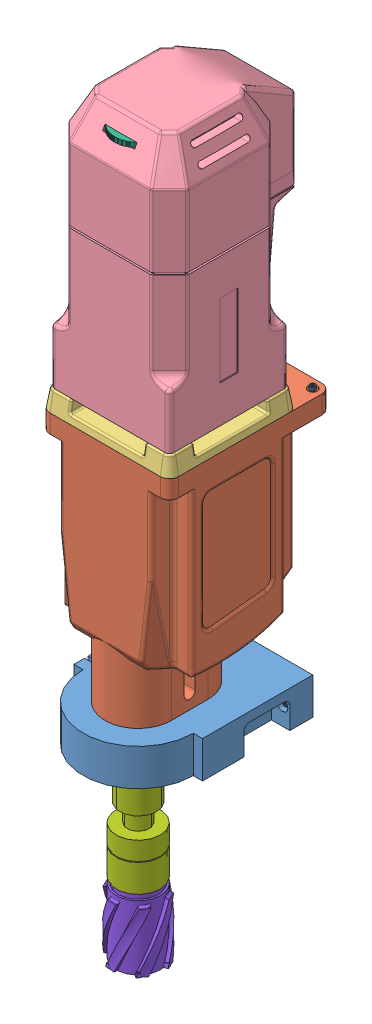
SolidWorks assembly Assembly, configuration Default. Lengths in mm.
Overall size (76 401.48 100).
18 component instances, 11 part files, 37 mates.
Components (placement in the parent):
- drill fixed plate-1: drill fixed plate [Default] at (-29.8336 37.5573 140.0225) x (-1 0 0) z (0 0 -1) size (70 20 90)
- drill floor fixed platform-1: drill floor fixed platform [Default] at (-29.8336 57.5573 160.0225) size (70.5 130 88)
- motor fixing plate-1: motor fixing plate [Default] at (-29.8336 187.5573 153.0225) size (70 10 70)
- motor-1: motor [默认] at (-29.8336 227.5573 153.0225) x (0 0 -1) z (0 -1 0) size (81.35 64.8 162.97)
- knob-1: knob [Default] at (-60.8336 142.5573 150.0225) x (-1 0 0) z (0 -0.897784 -0.440436) size (10 29 29)
- knob2-2: knob2 [Default] at (-29.8336 327.5573 170.4201) x (0.971097 0 0.238684) z (-0.238684 0 0.971097) size (24.99 2.5 24.99)
- drill fixture-1: drill fixture [Default] at (-29.8336 35.5573 170.0225) x (-0.675418 0 -0.737435) z (-0.737435 0 0.675418) size (24 110.5 24)
- drill-1: drill [Default] at (-29.8336 -62.9427 170.0225) x (0.989156 0 0.146869) z (-0.146869 0 0.989156) size (27.89 50.01 31.09)
- angular contact ball bearings gb-1: angular contact ball bearings gb [PreviewCfg] at (-29.8336 39.5573 170.0225) x (0 -1 0) z (0 0 1) size (4 11 11)
- hexagon socket head cap screws gb-1: hexagon socket head cap screws gb [PreviewCfg] at (0.1664 175.9573 182.0225) x (0 1 0) z (0 0 1) size (7.6 3 3)
- hexagon socket head cap screws gb-2: hexagon socket head cap screws gb [PreviewCfg] at (-59.8336 175.9573 182.0225) x (0 1 0) z (0 0 1) size (7.6 3 3)
- hexagon socket head cap screws gb-3: hexagon socket head cap screws gb [PreviewCfg] at (0.1664 175.9573 122.0225) x (0 1 0) z (0 0 1) size (7.6 3 3)
- hexagon socket head cap screws gb-4: hexagon socket head cap screws gb [PreviewCfg] at (-59.8336 175.9573 122.0225) x (0 1 0) z (0 0 1) size (7.6 3 3)
- hexagon socket head cap screws gb-6: hexagon socket head cap screws gb [PreviewCfg] at (0.1664 189.1573 105.0225) x (0 -1 0) z (-0.996731 0 -0.080796) size (7.6 3 3)
- hexagon socket head cap screws gb-7: hexagon socket head cap screws gb [PreviewCfg] at (-59.8336 189.1573 105.0225) x (0 -1 0) z (-0.996731 0 -0.080796) size (7.6 3 3)
- hexagon socket head cap screws gb-8: hexagon socket head cap screws gb [PreviewCfg] at (-60.8336 47.5573 121.1225) x (0 0 -1) z (1 0 0) size (7.6 3 3)
- hexagon socket head cap screws gb-11: hexagon socket head cap screws gb [PreviewCfg] at (1.1664 47.5573 121.1225) x (0 0 -1) z (1 0 0) size (7.6 3 3)
- hexagon socket button head screws gb-1: hexagon socket button head screws gb [PreviewCfg] at (-60.8336 47.5573 168.3225) x (0 0 -1) z (0.073283 0.997311 0) size (23.3 12 12)
Mates (geometry in assembly coordinates):
- 重合20: coincident anti-aligned: plane of 钻头固定板-1 through (-29.8336 57.5573 140.0225) normal (0 1 0); plane of 钻台固定台-1 through (-29.8336 57.5573 150.0225) normal (0 -1 0)
- 同心2: concentric aligned: cylinder of 钻头固定板-1 through (-29.8336 57.5573 170.0225) axis (0 -1 0) radius 15; cylinder of 钻台固定台-1 through (-29.8336 87.5573 170.0225) axis (0 -1 0) radius 18
- 平行4: parallel aligned: plane of 钻头固定板-1 through (5.1664 57.5573 140.0225) normal (1 0 0); plane of 钻台固定台-1 through (-11.8336 87.5573 150.0225) normal (1 0 0)
- 重合24: coincident anti-aligned: plane of 钻台固定台-1 through (-29.8336 187.5573 160.0225) normal (0 1 0); plane of 电动机固定板-1 through (-59.8336 187.5573 183.0225) normal (0 -1 0)
- 重合25: coincident: plane of 钻台固定台-1 through (-64.8336 177.5573 188.0225) normal (0 0 1); line of 电动机固定板-1 through (-59.8336 187.5573 188.0225) axis (1 0 0)
- 重合26: coincident: plane of 钻台固定台-1 through (5.1664 177.5573 110.0225) normal (1 0 0); line of 电动机固定板-1 through (5.1664 187.5573 183.0225) axis (0 0 -1)
- 重合27: coincident anti-aligned: plane of 电动机固定板-1 through (-59.8336 197.5573 183.0225) normal (0 1 0); plane of 电机-1 through (-29.8336 197.5573 153.0225) normal (0 -1 0)
- 同心3: concentric aligned: cone of 电动机固定板-1 through (0.1664 187.5573 123.0225) axis (0 1 0); cylinder of 电机-1 through (0.1664 197.5573 123.0225) axis (0 1 0) radius 2.3976
- 同心4: concentric aligned: cone of 电动机固定板-1 through (-59.8336 187.5573 123.0225) axis (0 1 0); cylinder of 电机-1 through (-59.8336 197.5573 123.0225) axis (0 1 0) radius 2.3976
- 重合28: coincident anti-aligned: plane of 钻台固定台-1 through (-60.8336 142.5573 150.0225) normal (-1 0 0); plane of 旋钮-1 through (-60.8336 142.5573 150.0225) normal (1 0 0)
- 同心5: concentric anti-aligned: circle of 钻台固定台-1; cylinder of 旋钮-1 through (-65.8336 142.5573 150.0225) axis (1 0 0) radius 14.5
- 重合32: coincident anti-aligned: plane of 电机-1 through (-29.8336 330.0573 170.4201) normal (0 -1 0); plane of 旋钮2-2 through (-29.8336 330.0573 170.4201) normal (0 1 0)
- 同心9: concentric anti-aligned: circle of 电机-1; circle of 旋钮2-2
- 同心10: concentric anti-aligned: cylinder of 钻头固定板-1 through (-29.8336 57.5573 170.0225) axis (0 -1 0) radius 15; cylinder of 钻头夹具-1 through (-29.8336 10.5573 170.0225) axis (0 1 0) radius 10
- 同心11: concentric anti-aligned: cylinder of 钻头固定板-1 through (-29.8336 57.5573 170.0225) axis (0 -1 0) radius 15; cylinder of angular contact ball bearings gb-1 through (-29.8336 42.5497 170.0225) axis (0 1 0) radius 2
- 重合34: coincident aligned: plane of 钻头固定板-1 through (-29.8336 37.5573 140.0225) normal (0 -1 0); plane of angular contact ball bearings gb-1 through (-26.6669 37.5573 170.0225) normal (0 -1 0)
- 距离5: distance = 2 mm anti-aligned: plane of 钻头夹具-1 through (-29.8336 35.5573 170.0225) normal (0 1 0); plane of 钻头固定板-1 through (-29.8336 37.5573 140.0225) normal (0 -1 0)
- 同心12: concentric aligned: cylinder of 钻头夹具-1 through (-29.8336 -12.9427 170.0225) axis (0 -1 0) radius 11; cylinder of 钻头-1 through (-29.8336 -12.9427 170.0225) axis (0 -1 0) radius 11
- 重合39: coincident anti-aligned: plane of 钻头夹具-1 through (-29.8336 -12.9427 170.0225) normal (0 -1 0); plane of 钻头-1 through (-29.8336 -12.9427 170.0225) normal (0 1 0)
- 同心15: concentric aligned: cylinder of 钻台固定台-1 through (0.1664 187.5573 182.0225) axis (0 -1 0) radius 2; cylinder of hexagon socket head cap screws gb-1 through (0.1664 177.5573 182.0225) axis (0 -1 0) radius 1.5
- 重合42: coincident anti-aligned: plane of 钻台固定台-1 through (-29.8336 177.5573 160.0225) normal (0 -1 0); plane of hexagon socket head cap screws gb-1 through (0.1664 177.5573 182.0225) normal (0 1 0)
- 重合43: coincident anti-aligned: plane of 钻台固定台-1 through (-29.8336 177.5573 160.0225) normal (0 -1 0); plane of hexagon socket head cap screws gb-2 through (-59.8336 177.5573 182.0225) normal (0 1 0)
- 同心16: concentric aligned: cylinder of 钻台固定台-1 through (-59.8336 187.5573 182.0225) axis (0 -1 0) radius 2; cylinder of hexagon socket head cap screws gb-2 through (-59.8336 177.5573 182.0225) axis (0 -1 0) radius 1.5
- 同心17: concentric aligned: cylinder of 钻台固定台-1 through (0.1664 187.5573 122.0225) axis (0 -1 0) radius 2; cylinder of hexagon socket head cap screws gb-3 through (0.1664 177.5573 122.0225) axis (0 -1 0) radius 1.5
- 重合44: coincident anti-aligned: plane of 钻台固定台-1 through (-29.8336 177.5573 160.0225) normal (0 -1 0); plane of hexagon socket head cap screws gb-3 through (0.1664 177.5573 122.0225) normal (0 1 0)
- 同心18: concentric aligned: cylinder of 钻台固定台-1 through (-59.8336 187.5573 122.0225) axis (0 -1 0) radius 2; cylinder of hexagon socket head cap screws gb-4 through (-59.8336 177.5573 122.0225) axis (0 -1 0) radius 1.5
- 重合45: coincident anti-aligned: plane of 钻台固定台-1 through (-29.8336 177.5573 160.0225) normal (0 -1 0); plane of hexagon socket head cap screws gb-4 through (-59.8336 177.5573 122.0225) normal (0 1 0)
- 同心20: concentric anti-aligned: cylinder of 钻台固定台-1 through (0.1664 337.5573 105.0225) axis (0 -1 0) radius 2.5; cylinder of hexagon socket head cap screws gb-6 through (0.1664 187.5573 105.0225) axis (0 1 0) radius 1.5
- 重合46: coincident anti-aligned: plane of 钻台固定台-1 through (-29.8336 187.5573 160.0225) normal (0 1 0); plane of hexagon socket head cap screws gb-6 through (0.1664 187.5573 105.0225) normal (0 -1 0)
- 重合47: coincident anti-aligned: plane of 钻台固定台-1 through (-29.8336 187.5573 160.0225) normal (0 1 0); plane of hexagon socket head cap screws gb-7 through (-59.8336 187.5573 105.0225) normal (0 -1 0)
- 同心21: concentric anti-aligned: cylinder of 钻台固定台-1 through (-59.8336 337.5573 105.0225) axis (0 -1 0) radius 2.5; cylinder of hexagon socket head cap screws gb-7 through (-59.8336 187.5573 105.0225) axis (0 1 0) radius 1.5
- 重合48: coincident anti-aligned: plane of 钻头固定板-1 through (-60.8336 47.5573 119.5225) normal (0 0 1); plane of hexagon socket head cap screws gb-8 through (-60.8336 47.5573 119.5225) normal (0 0 -1)
- 同心22: concentric anti-aligned: cylinder of 钻头固定板-1 through (-60.8336 47.5573 125.5225) axis (0 0 -1) radius 3; cylinder of hexagon socket head cap screws gb-8 through (-60.8336 47.5573 119.5225) axis (0 0 1) radius 1.5
- 重合51: coincident anti-aligned: plane of 钻头固定板-1 through (1.1664 47.5573 119.5225) normal (0 0 1); plane of hexagon socket head cap screws gb-11 through (1.1664 47.5573 119.5225) normal (0 0 -1)
- 同心26: concentric aligned: cylinder of 钻头固定板-1 through (1.1664 47.5573 77.5225) axis (0 0 1) radius 2; cylinder of hexagon socket head cap screws gb-11 through (1.1664 47.5573 119.5225) axis (0 0 1) radius 1.5
- 同心28: concentric anti-aligned: cylinder of 钻头固定板-1 through (-60.8336 47.5573 223.0225) axis (0 0 -1) radius 3; circle of hexagon socket button head screws gb-1
- 重合52: coincident anti-aligned: plane of 钻头固定板-1 through (-60.8336 47.5573 165.0225) normal (0 0 1); plane of hexagon socket button head screws gb-1 through (-60.8336 47.5573 165.0225) normal (0 0 -1)
